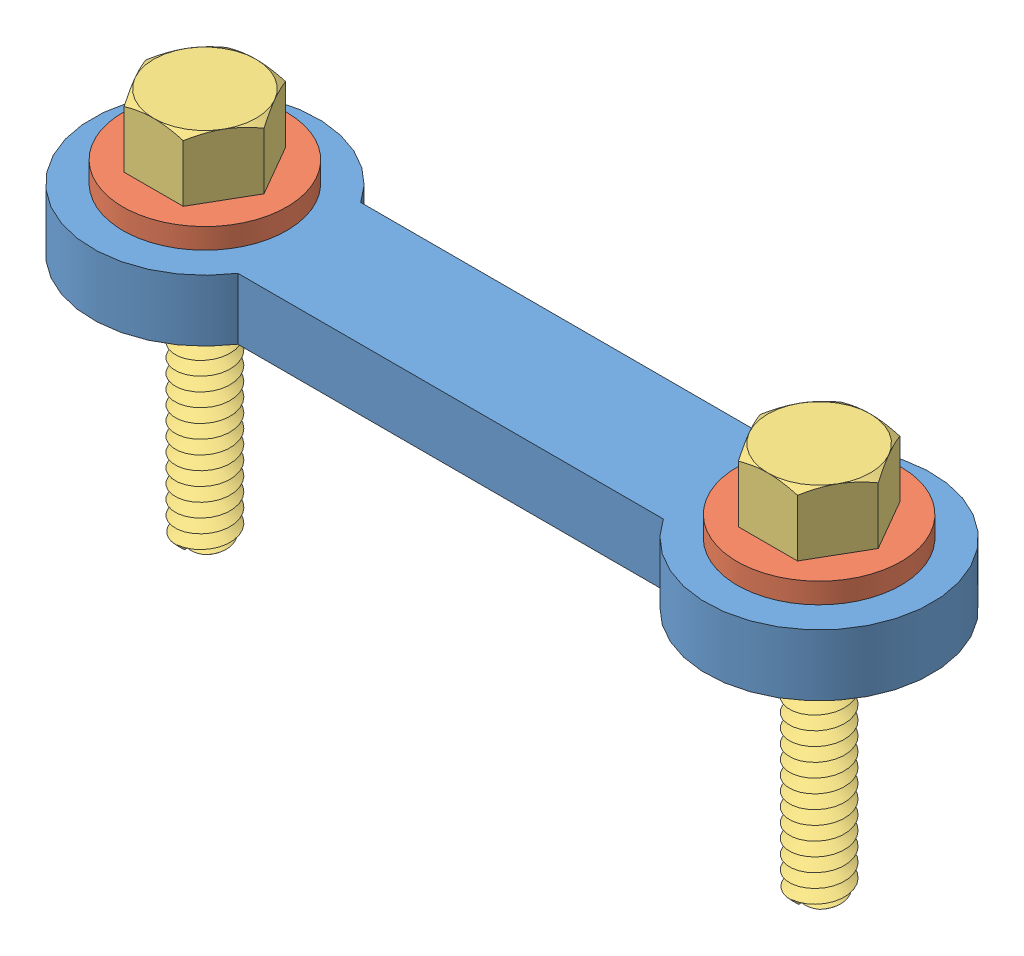
SolidWorks assembly Assem7_4, configuration Default. Lengths in mm.
Overall size (41 19.28 11).
6 component instances, 3 part files, 15 mates.
Components (placement in the parent):
- Part16-1: Part16 [Default] at origin size (41 3 11)
- sajbna7-1: sajbna7 [Default] at (0 3 0) size (8 1 8)
- sajbna7-2: sajbna7 [Default] at (30 3 0) size (8 1 8)
- sajbna7-3: sajbna7 [Default] at (30 -1 0) size (8 1 8)
- straf3_dolg16_3-1: straf3_dolg16_3 [Default] at (0 4 0) x (0 1 0) z (0 0 1) size (19.28 5.77 5)
- straf3_dolg16_3-2: straf3_dolg16_3 [Default] at (30 4 0) x (0 1 0) z (0 0 1) size (19.28 5.77 5)
Mates (geometry in assembly coordinates):
- Concentric1: concentric aligned: cylinder of Part16-1 through (0 3 0) axis (0 -1 0) radius 1.5; cylinder of sajbna7-1 through (0 4 0) axis (0 -1 0) radius 1.5
- Coincident1: coincident anti-aligned: plane of Part16-1 through (0 3 0) normal (0 1 0); plane of sajbna7-1 through (0 3 0) normal (0 -1 0)
- Concentric2: concentric anti-aligned: cylinder of Part16-1 through (0 3 0) axis (0 -1 0) radius 1.5; cylinder of straf3_dolg16_3-1 through (0 -12 0) axis (0 1 0) radius 1.5
- Coincident2: coincident anti-aligned: plane of sajbna7-1 through (0 4 0) normal (0 1 0); plane of straf3_dolg16_3-1 through (0 4 0) normal (0 -1 0)
- Concentric3: concentric aligned: cylinder of Part16-1 through (30 3 0) axis (0 -1 0) radius 1.5; cylinder of sajbna7-2 through (30 4 0) axis (0 -1 0) radius 1.5
- Coincident3: coincident anti-aligned: plane of Part16-1 through (0 3 0) normal (0 1 0); plane of sajbna7-2 through (30 3 0) normal (0 -1 0)
- Concentric4: concentric aligned: cylinder of Part16-1 through (30 3 0) axis (0 -1 0) radius 1.5; cylinder of sajbna7-3 through (30 0 0) axis (0 -1 0) radius 1.5
- Coincident4: coincident anti-aligned: plane of Part16-1 through (0 0 0) normal (0 -1 0); plane of sajbna7-3 through (30 0 0) normal (0 1 0)
- Concentric5: concentric anti-aligned: cylinder of Part16-1 through (30 3 0) axis (0 -1 0) radius 1.5; cylinder of straf3_dolg16_3-2 through (30 -12 0) axis (0 1 0) radius 1.5
- Coincident5: coincident anti-aligned: plane of sajbna7-2 through (30 4 0) normal (0 1 0); plane of straf3_dolg16_3-2 through (30 4 0) normal (0 -1 0)
- Parallel1: parallel aligned: plane of sajbna7-1 through (0 3 0) normal (0 0 1); plane of assembly
- Parallel2: parallel aligned: plane of sajbna7-2 through (30 3 0) normal (0 0 1); plane of assembly
- Parallel3: parallel aligned: plane of sajbna7-3 through (30 -1 0) normal (0 0 1); plane of assembly
- Parallel4: parallel aligned: plane of straf3_dolg16_3-1 through (0 4 0) normal (0 0 1); plane of assembly
- Parallel5: parallel aligned: plane of straf3_dolg16_3-2 through (30 4 0) normal (0 0 1); plane of assembly
